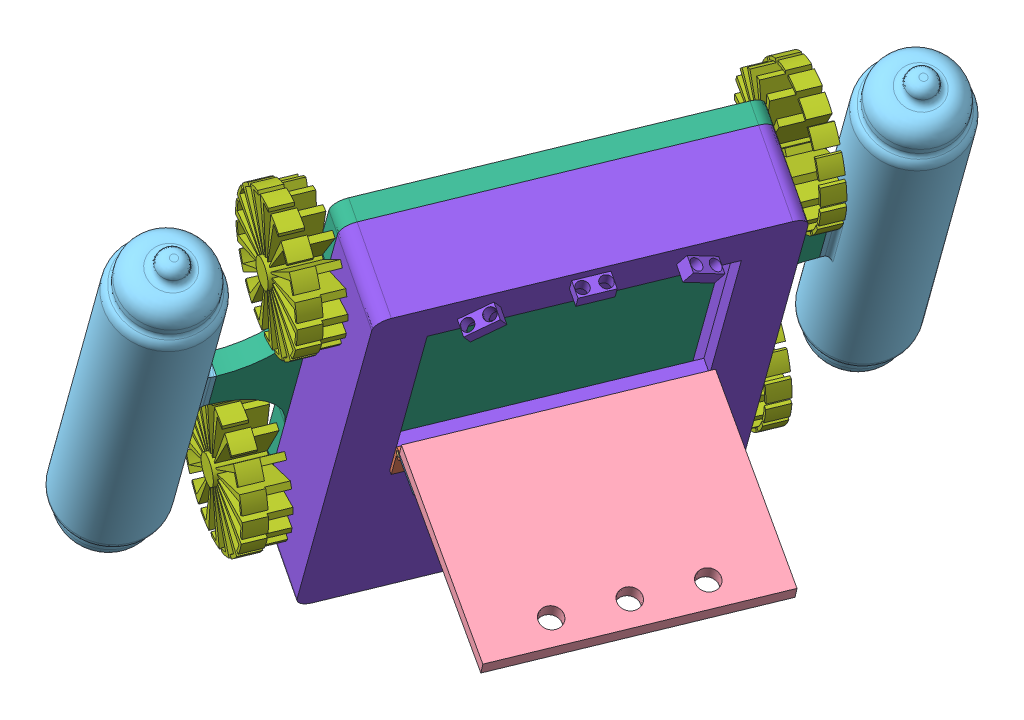
SolidWorks assembly Assieme1, configuration Default. Lengths in mm.
Overall size (949.61 808.15 1173.45).
18 component instances, 8 part files, 11 mates.
Components (placement in the parent):
- Complete Hinge-1: Complete Hinge [Default] at (-400.8258 1197.2473 1242.8385) x (0.713978 -0.126891 -0.688574) z (0.380791 0.895654 0.229788) size (116.85 97.34 61.91)
  - Hinge 1-1: Hinge 1 [Default] at (227.1069 4.4476 137.0094) x (0.923728 0.383049 0) z (0 0 1) size (100 61.24 15)
  - Hinge 2-1: Hinge 2 [Default] at (214.9756 33.7026 106.878) x (-0.923728 -0.383049 0) z (-0.382574 0.922583 0.049778) size (100 61.24 15)
  - Hinge screw-1: Hinge screw [Default] at (168.7892 14.5501 106.878) x (0.382574 -0.922583 -0.049778) z (-0.923728 -0.383049 0) size (8.06 8.06 100)
- Cover cap-1: Cover cap [Default] at (-29.2513 1270.5472 1046.4221) x (-0.434455 -0.046068 0.899514) z (-0.380791 -0.895654 -0.229788) size (360 280 20)
- First assembly-1: First assembly [Default] at (-392.3333 827.1854 441.3574) x (-0.434455 -0.046068 0.899514) z (0.42095 0.872523 0.248) size (998.86 263.45 726.63)
  - Air Tank-1: Air Tank [Default] at (-63.4415 1.2515 650) size (149.43 140 650)
  - Air Tank-2: Air Tank [Default] at (795.4215 1.2515 650) x (-1 0 0) z (0 0 -1) size (149.43 140 650)
  - Base-1: Base [Default] at (165.4585 22.3484 980.1174) x (1 0 0) z (0 -1 0) size (700 700 30)
  - Wheel-1: Wheel [Default] at (80.99 7.3484 409.2812) x (0 0 1) z (-1 0 0) size (200 200 65)
  - Wheel-2: Wheel [Default] at (80.99 7.3484 893.0938) x (0 0 1) z (-1 0 0) size (200 200 65)
  - Wheel-3: Wheel [Default] at (650.99 7.3484 893.0938) x (0 0.993029 -0.117873) z (1 0 0) size (200 200 65)
  - Wheel-4: Wheel [Default] at (650.99 7.3484 409.2812) x (0 0.915955 -0.401282) z (1 0 0) size (200 200 65)
- Top cover-1: Top cover [Default] at (-218.0184 1026.1615 664.6874) x (-0.434455 -0.046068 0.899514) z (0.796273 -0.486395 0.35968) size (500 700 142)
- Complete Hinge-2: Complete Hinge [Default] at (-287.8674 1209.2251 1008.9647) x (0.713978 -0.126891 -0.688574) z (0.380791 0.895654 0.229788) size (116.85 97.34 61.91)
  - Hinge 1-1: Hinge 1 [Default] at (227.1069 4.4476 137.0094) x (0.923728 0.383049 0) z (0 0 1) size (100 61.24 15)
  - Hinge 2-1: Hinge 2 [Default] at (214.9756 33.7026 106.878) x (-0.923728 -0.383049 0) z (-0.382574 0.922583 0.049778) size (100 61.24 15)
  - Hinge screw-1: Hinge screw [Default] at (168.7892 14.5501 106.878) x (0.382574 -0.922583 -0.049778) z (-0.923728 -0.383049 0) size (8.06 8.06 100)
Mates (geometry in assembly coordinates):
- Coincidente1: coincident anti-aligned: plane of First assembly-1/Base-1 through (-33.842 1663.8683 841.2973) normal (0.796273 -0.486395 0.35968); plane of Top cover-1 through (-297.6457 1074.801 628.7194) normal (-0.796273 0.486395 -0.35968)
- Coincidente2: coincident aligned: line of First assembly-1/Base-1 through (-11.67 1684.6461 820.3098) axis (-0.434455 -0.046068 0.899514); line of Top cover-1 through (-11.67 1684.6461 820.3098) axis (-0.434455 -0.046068 0.899514)
- Coincidente3: coincident aligned: line of First assembly-1/Base-1 through (-424.869 1238.3232 1131.5022) axis (-0.42095 -0.872523 -0.248); line of Top cover-1 through (-228.6275 1645.0828 1247.1167) axis (-0.42095 -0.872523 -0.248)
- Coincidente6: coincident anti-aligned: plane of Cover cap-1 through (-36.8671 1252.6342 1041.8263) normal (-0.380791 -0.895654 -0.229788); plane of Complete Hinge-2/Hinge 1-1 through (-74.2554 1309.4944 882.1579) normal (0.380791 0.895654 0.229788)
- Coincidente7: coincident anti-aligned: line of Cover cap-1 through (-229.3426 1306.2722 1151.7179) axis (0.434455 0.046068 -0.899514); line of Complete Hinge-2/Hinge 1-1 through (-81.6278 1321.9355 845.883) axis (-0.434455 -0.046068 0.899514)
- Coincidente9: coincident anti-aligned: plane of Complete Hinge-1/Hinge 1-1 through (-187.2138 1297.5166 1116.0316) normal (0.380791 0.895654 0.229788); plane of Cover cap-1 through (-36.8671 1252.6342 1041.8263) normal (-0.380791 -0.895654 -0.229788)
- Coincidente10: coincident aligned: line of Complete Hinge-1/Hinge 1-1 through (-220.6535 1307.1935 1133.7276) axis (0.434455 0.046068 -0.899514); line of Cover cap-1 through (-229.3426 1306.2722 1151.7179) axis (0.434455 0.046068 -0.899514)
- Coincidente12: coincident anti-aligned: line of Cover cap-1 through (-72.9386 1322.8568 827.8927) axis (0.81624 -0.44236 0.371579); line of Complete Hinge-2/Hinge 1-1 through (-32.1267 1300.7389 846.4716) axis (-0.81624 0.44236 -0.371579)
- Coincidente13: coincident anti-aligned: line of Complete Hinge-1/Hinge 1-1 through (-229.3426 1306.2722 1151.7179) axis (0.81624 -0.44236 0.371579); line of Cover cap-1 through (-0.7955 1182.4115 1255.76) axis (-0.81624 0.44236 -0.371579)
- Coincidente23: coincident anti-aligned: plane of Top cover-1 through (-202.093 1016.4336 671.881) normal (0.796273 -0.486395 0.35968); plane of Complete Hinge-2/Hinge 2-1 through (-117.4652 1294.4706 860.5186) normal (-0.796273 0.486395 -0.35968)
- Coincidente24: coincident anti-aligned: line of Top cover-1 through (-85.1724 1318.592 821.6471) axis (-0.434455 -0.046068 0.899514); line of Complete Hinge-2/Hinge 2-1 through (-102.5969 1316.7444 857.7235) axis (0.434455 0.046068 -0.899514)
